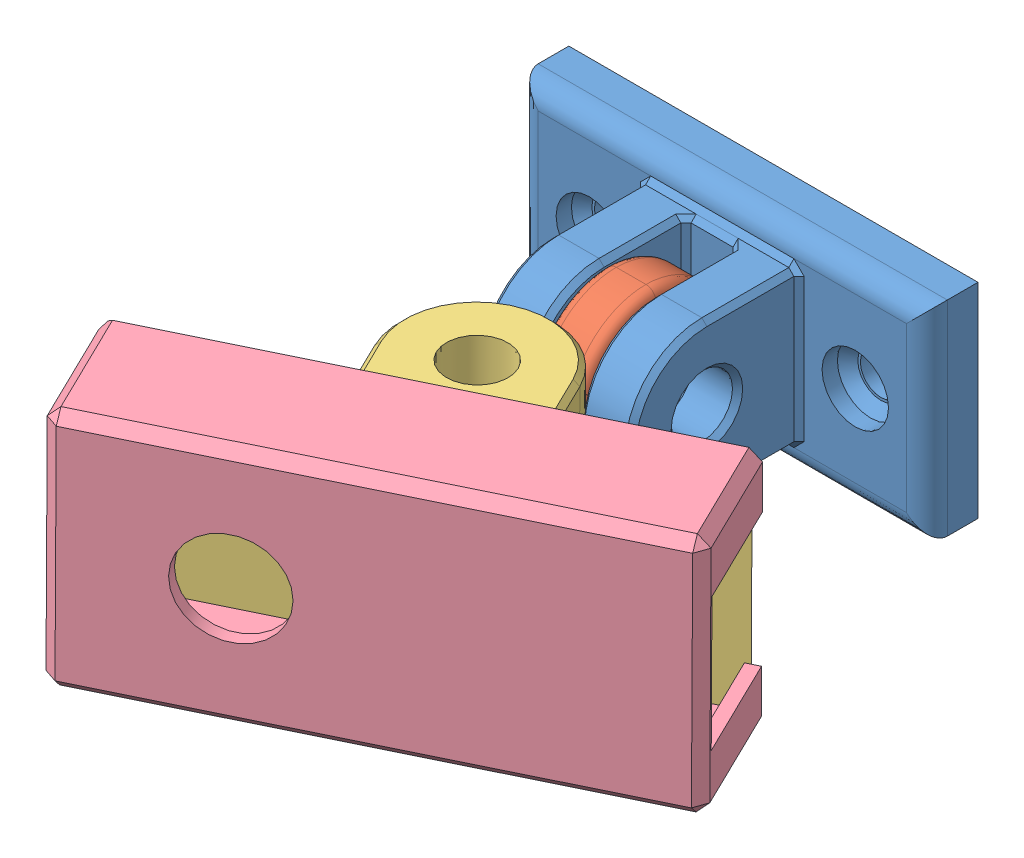
SolidWorks assembly Assem1, configuration Default. Lengths in mm.
Overall size (55.86 23.68 59.49).
4 component instances, 4 part files, 8 mates.
Components (placement in the parent):
- wall-1: wall [Default] at (-19.1517 -4.3102 2.2844) size (40 20 21.5)
- pole-1: pole [Default] at (-19.1517 -4.3521 8.7845) x (0 0.005587 0.999984) z (0 -0.999984 0.005587) size (30 15.11 15.11)
- back-1: back [Default] at (-14.7501 -3.8762 40.2615) x (0 0.999984 -0.005587) z (-0.440163 -0.005016 -0.897904) size (21.25 47 17.5)
- body-1: body [Default] at (-9.4682 -3.441 51.0343) x (0.897918 -0.002459 -0.440156) z (-0.440163 -0.005016 -0.897904) size (48.5 23.5 13)
Mates (geometry in assembly coordinates):
- Concentric3: concentric anti-aligned: circle of pole-1; circle of back-1
- Distance3: distance = 0.1 mm anti-aligned: plane of back-1 through (-9.1161 -6.5572 34.7304) normal (0 0.999984 -0.005587); plane of pole-1 through (-11.6517 -6.721 23.298) normal (0 -0.999984 0.005587)
- Coincident7: coincident anti-aligned: plane of back-1 through (-14.7501 -3.8762 40.2615) normal (0.440163 0.005016 0.897904); plane of body-1 through (-14.7501 -3.5012 40.2594) normal (-0.440163 -0.005016 -0.897904)
- Parallel2: parallel anti-aligned: line of back-1 through (-35.8512 -14.4433 50.6645) axis (0 0.999984 -0.005587); line of body-1 through (-35.8512 7.5564 50.5416) axis (0 -0.999984 0.005587)
- Coincident10: coincident anti-aligned: line of back-1 through (6.351 -14.5588 29.9772) axis (-0.897918 0.002459 0.440156); line of body-1 through (-35.8512 -14.4433 50.6645) axis (0.897918 -0.002459 -0.440156)
- Coincident11: coincident: line of back-1 through (-35.8512 -14.4433 50.6645) axis (0 0.999984 -0.005587); plane of body-1 through (-35.3934 8.5239 49.1981) normal (0.946166 0.001808 0.323677)
- Concentric4: concentric aligned: circle of wall-1; circle of pole-1
- Distance5: distance = 0.1 mm anti-aligned: plane of wall-1 through (-21.7017 3.1898 23.7844) normal (1 0 0); plane of pole-1 through (-21.6017 -11.7654 24.3262) normal (-1 0 0)
